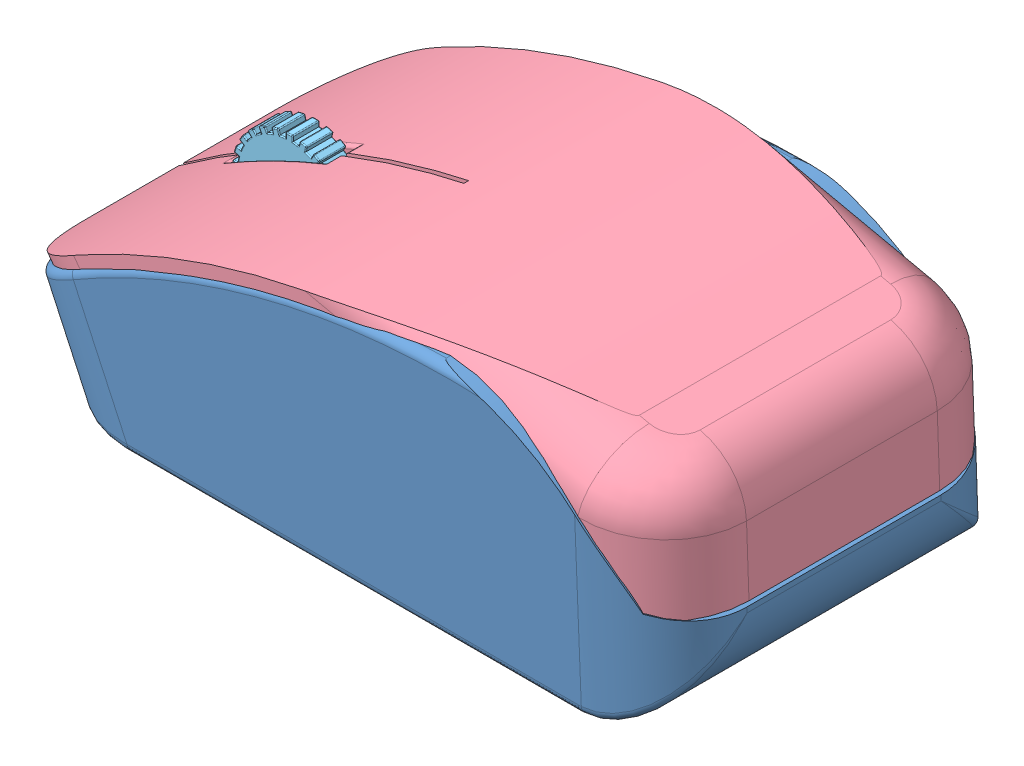
SolidWorks assembly Computer Mouse Assembly, configuration Default. Lengths in mm.
Overall size (100.33 37.12 61.28).
11 component instances, 10 part files, 0 mates.
Components (placement in the parent):
- Mouse Body-1: Mouse Body [Default] at (52.9762 55.6475 67.0047) size (100.21 35.27 57.74)
- Bottom Cover-1: Bottom Cover [Default] at (27.3346 57.3723 115.2019) x (1 0 0) z (0 -0.008727 -0.999962) size (43.84 1.27 24.37)
- LED Diode-1: LED Diode [Default] at (56.156 61.583 79.4106) x (0.906308 -0.422618 0) z (0 0 1) size (4.51 17.27 4.51)
- Top Cover-1: Top Cover [Default] at (52.2493 58.0865 67.2689) size (100.33 23.49 61.1)
- Scroll Wheel-1: Scroll Wheel [Default] at (21.9296 75.9132 92.53) size (17.2 17.17 12.19)
- On Button-1: On Button [Default] at (80.4151 56.9013 94.4898) size (8.22 5.33 8.22)
- Mirror-1: Mirror [Default] at (61.3697 54.9758 76.5973) x (-0.008503 0.001963 0.999962) z (-0.974333 0.224942 -0.008727) size (5.84 5.52 7.15)
- Glidey Pad-1: Glidey Pad [Default] at (18.3947 56.1068 92.4502) x (0.999848 0 0.017452) z (-0.000152 -0.999962 0.008725) size (13.63 46.98 0.82)
- Glidey Pad-2: Glidey Pad [Default] at (81.9887 55.217 92.7992) x (-0.99981 0.008725 0.017452) z (0.008878 0.999923 0.008725) size (13.63 46.98 0.82)
- Battery-1: Battery [Default] at (75.9228 60.3645 125.2957) size (42.83 8.56 8.56)
- Spring-1: Spring [Default] at (71.1704 59.1571 109.0655) x (0.008727 0.999962 0) z (0 0 1) size (4.81 1.9 5.09)
